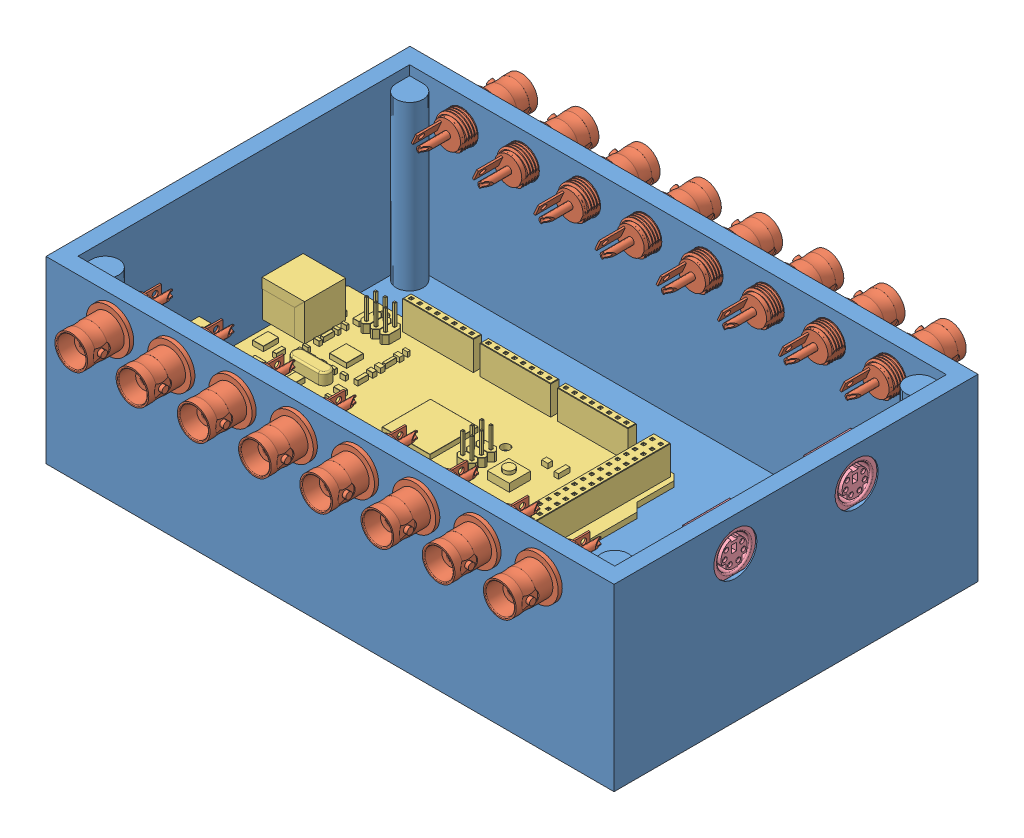
SolidWorks assembly AuroraBigger, configuration Default. Lengths in mm.
Overall size (167 53.21 132.33).
20 component instances, 4 part files, 5 mates.
Components (placement in the parent):
- enclosure2-1: enclosure2 [Default] at (49.0204 78.7138 140.9448) size (167 52.8 107)
- Amphenal_031_10_RFXG1-1: Amphenal_031_10_RFXG1 [Default] at (151.3133 106.1134 196.4731) size (12.75 12.75 29.79)
- ArduinoMega-1: ArduinoMega [Default] at (10.821 88.3188 151.7131) x (-1 0 0) z (0 -1 0) size (107.95 53.42 12.95)
- connector-1: connector [Default] at (119.4662 115.3741 162.4869) x (0 -0.001472 0.999999) z (-1 0 0) size (14 12.6 8.3)
- Amphenal_031_10_RFXG1-2: Amphenal_031_10_RFXG1 [Default] at (133.3133 106.1134 196.4731) size (12.75 12.75 29.79)
- Amphenal_031_10_RFXG1-3: Amphenal_031_10_RFXG1 [Default] at (115.3133 106.1134 196.4731) size (12.75 12.75 29.79)
- Amphenal_031_10_RFXG1-4: Amphenal_031_10_RFXG1 [Default] at (97.3133 106.1134 196.4731) size (12.75 12.75 29.79)
- Amphenal_031_10_RFXG1-5: Amphenal_031_10_RFXG1 [Default] at (79.3133 106.1134 196.4731) size (12.75 12.75 29.79)
- Amphenal_031_10_RFXG1-6: Amphenal_031_10_RFXG1 [Default] at (61.3133 106.1134 196.4731) size (12.75 12.75 29.79)
- Amphenal_031_10_RFXG1-7: Amphenal_031_10_RFXG1 [Default] at (43.3133 106.1134 196.4731) size (12.75 12.75 29.79)
- Amphenal_031_10_RFXG1-8: Amphenal_031_10_RFXG1 [Default] at (25.3133 106.1134 196.4731) size (12.75 12.75 29.79)
- Amphenal_031_10_RFXG1-9: Amphenal_031_10_RFXG1 [Default] at (153.8689 118.2224 106.6847) x (0.914719 -0.404089 0) z (0 0 -1) size (12.75 12.75 29.79)
- Amphenal_031_10_RFXG1-10: Amphenal_031_10_RFXG1 [Default] at (135.8689 118.2224 106.6847) x (0.914719 -0.404089 0) z (0 0 -1) size (12.75 12.75 29.79)
- Amphenal_031_10_RFXG1-11: Amphenal_031_10_RFXG1 [Default] at (117.8689 118.2224 106.6847) x (0.914719 -0.404089 0) z (0 0 -1) size (12.75 12.75 29.79)
- Amphenal_031_10_RFXG1-12: Amphenal_031_10_RFXG1 [Default] at (99.8689 118.2224 106.6847) x (0.914719 -0.404089 0) z (0 0 -1) size (12.75 12.75 29.79)
- Amphenal_031_10_RFXG1-13: Amphenal_031_10_RFXG1 [Default] at (81.8689 118.2224 106.6847) x (0.914719 -0.404089 0) z (0 0 -1) size (12.75 12.75 29.79)
- Amphenal_031_10_RFXG1-14: Amphenal_031_10_RFXG1 [Default] at (63.8689 118.2224 106.6847) x (0.914719 -0.404089 0) z (0 0 -1) size (12.75 12.75 29.79)
- Amphenal_031_10_RFXG1-15: Amphenal_031_10_RFXG1 [Default] at (45.8689 118.2224 106.6847) x (0.914719 -0.404089 0) z (0 0 -1) size (12.75 12.75 29.79)
- Amphenal_031_10_RFXG1-16: Amphenal_031_10_RFXG1 [Default] at (27.8689 118.2224 106.6847) x (0.914719 -0.404089 0) z (0 0 -1) size (12.75 12.75 29.79)
- connector-2: connector [Default] at (119.4662 115.3741 126.8869) x (0 -0.001472 0.999999) z (-1 0 0) size (14 12.6 8.3)
Mates (geometry in assembly coordinates):
- Coincident7: coincident: plane of enclosure2-1 through (119.831 99.1138 134.276) normal (0 -1 0); plane of ArduinoMega-1 through (-30.0222 99.1138 146.214) normal (0 1 0)
- Coincident11: coincident: plane of enclosure2-1 through (119.831 99.1138 134.276) normal (0 0 1); plane of ArduinoMega-1 through (-46.329 99.1138 134.276) normal (0 0 -1)
- Concentric1: concentric: circle of enclosure2-1; circle of Amphenal_031_10_RFXG1-1
- Concentric2: concentric: circle of enclosure2-1; circle of Amphenal_031_10_RFXG1-9
- Concentric3: concentric: circle of enclosure2-1; circle of connector-1
